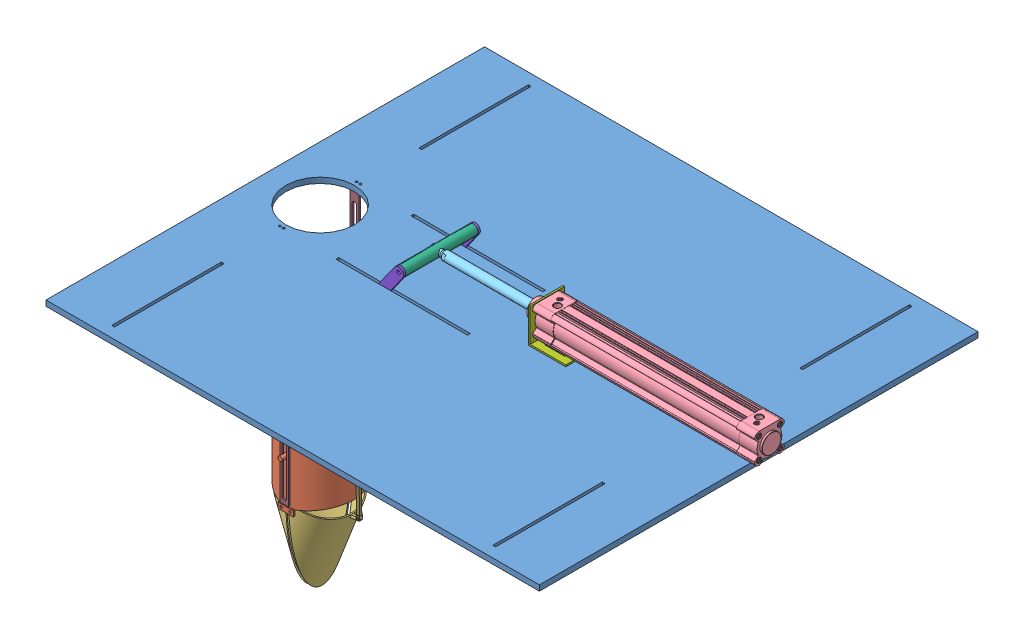
SolidWorks assembly Assem1, configuration Default. Lengths in mm.
Overall size (923.63 667.59 800).
24 component instances, 13 part files, 33 mates.
Components (placement in the parent):
- test_platform-1: test_platform [Default] at (230.5331 526.4519 836.3873) size (900 10 800)
- sub_assem_1-1: sub_assem_1 [Default] at (-22.5862 78.604 1012.0904) x (-1 0 0) z (0 0 -1) size (153.18 360.23 146)
  - sapling_cylinder-1: sapling_cylinder [Default] at (46.8806 8.4854 135.7031) size (134 210 146)
  - blade-1: blade [Default] at (44.3763 20.6048 75.7031) x (0.931286 0.364289 0) z (0 0 -1) size (71.09 159.46 120)
  - blade-2: blade [Default] at (49.414 20.6179 75.7031) x (-0.930414 0.366509 0) z (0 0 1) size (71.09 159.46 120)
- dsbc-40-300-ppva-n3-2: dsbc-40-300-ppva-n3 [Default] at (345.1649 571.4519 936.3873) x (0 0 1) z (-1 0 0) size (132 54 619.42) (flexible)
  - dsbc-40-300-ppva-n3_01-1: dsbc-40-300-ppva-n3_01 [Default] at origin size (54 54 430.3)
  - dsbc-40-300-ppva-n3_02-2: dsbc-40-300-ppva-n3_02 [Default] at (0 0 157.5173) x (0.967893 0.251361 0) z (0 0 1) size (40 40 424.9)
  - connecting_rod_1-1: connecting_rod_1 [Default] at (66 0 201.4173) x (0 1 0) z (-1 0 0) size (18 18 132)
- pneumatic_1_mount-1: pneumatic_1_mount [Default] at (376.9676 570.0281 904.8873) x (0 0 1) z (-1 0 0) size (63 63 68)
- connecting_rod-1: connecting_rod [Default] at (-60.0138 285.362 1002.3873) x (0.580128 0.814525 0) z (0 0 1) size (385.53 18 4)
- connecting_rod-2: connecting_rod [Default] at (-60.0138 285.362 866.3873) x (0.580128 0.814525 0) z (0 0 1) size (385.53 18 4)
- pneumatic_cylinder-1: pneumatic_cylinder [Default] at (30.9066 302.2621 990.5463) x (-1 0 0) z (0 -1 0) size (16 16 121.02) (flexible)
  - cylinder-1: cylinder [Default] at (30.3735 54.159 45.1726) size (16 16 94)
  - rod-1: rod [Default] at (30.3735 54.159 68.9064) x (-0.909841 -0.414956 0) z (0 0 1) size (12 12 85)
  - rod_end-1: rod_end [Default] at (30.3735 54.159 153.9064) x (0 1 0) z (0 0 -1) size (7 7 18)
- pneumatic_cylinder-3: pneumatic_cylinder [Default] at (-169.8404 302.2621 882.2284) x (1 0 0) z (0 -1 0) size (16 16 121.02) (flexible)
  - cylinder-1: cylinder [Default] at (30.3735 54.159 45.1726) size (16 16 94)
  - rod-1: rod [Default] at (30.3735 54.159 68.9064) x (0.259578 -0.965722 0) z (0 0 1) size (12 12 85)
  - rod_end-1: rod_end [Default] at (30.3735 54.159 153.9064) x (0 1 0) z (0 0 -1) size (7 7 18)
- connecting_rod_2-1: connecting_rod_2 [Default] at (-139.5802 143.7073 934.3873) x (0.019451 0.999811 0) z (0 0 1) size (71.5 5.5 7)
- connecting_rod_2-2: connecting_rod_2 [Default] at (0.5331 143.8558 934.3873) x (-0.021502 0.999769 0) z (0 0 1) size (71.5 5.5 7)
- rail-1: rail [Default] at (-77.4669 417.2853 914.2207) x (0 0 -1) z (1 0 0) size (12 430 16)
- rail-2: rail [Default] at (-61.4669 417.2853 958.554) x (0 0 1) z (-1 0 0) size (12 430 16)
Mates (geometry in assembly coordinates):
- Concentric1: concentric aligned: cylinder of test_platform-1 through (-69.4669 722.4519 936.3873) axis (0 -1 0) radius 62.5; cylinder of sub_assem_1-1/sapling_cylinder-1 through (-69.4669 292.0895 936.3873) axis (0 -1 0) radius 62
- Coincident1: coincident anti-aligned: plane of dsbc-40-300-ppva-n3-2/dsbc-40-300-ppva-n3_01-1 through (345.1649 589.6738 910.3873) normal (-1 0 0); plane of pneumatic_1_mount-1 through (345.1649 599.4519 967.8873) normal (1 0 0)
- Concentric2: concentric aligned: cylinder of dsbc-40-300-ppva-n3-2/dsbc-40-300-ppva-n3_01-1 through (345.1649 571.4519 936.3873) axis (-1 0 0) radius 17.5; cylinder of pneumatic_1_mount-1 through (410.1649 571.4519 936.3873) axis (-1 0 0) radius 20
- Concentric3: concentric aligned: cylinder of dsbc-40-300-ppva-n3-2/dsbc-40-300-ppva-n3_01-1 through (365.2843 590.4519 917.3873) axis (-1 0 0) radius 2.4585; cylinder of pneumatic_1_mount-1 through (410.1649 590.4519 917.3873) axis (-1 0 0) radius 4.75
- Coincident2: coincident aligned: plane of test_platform-1 through (395.9402 536.4519 949.1373) normal (0 0 1); plane of pneumatic_1_mount-1 through (395.9402 536.4519 949.1373) normal (0 0 1)
- Coincident3: coincident aligned: plane of test_platform-1 through (395.9402 536.4519 949.1373) normal (-1 0 0); plane of pneumatic_1_mount-1 through (395.9402 536.4519 955.1373) normal (-1 0 0)
- Coincident4: coincident anti-aligned: plane of test_platform-1 through (230.5331 536.4519 836.3873) normal (0 1 0); plane of pneumatic_1_mount-1 through (410.1649 536.4519 967.8873) normal (0 -1 0)
- Parallel1: parallel aligned: plane of test_platform-1 through (-169.4669 536.4519 1336.3873) normal (0 0 1); plane of sub_assem_1-1/sapling_cylinder-1 through (-69.4669 87.0895 999.3873) normal (0 0 1)
- Concentric4: concentric anti-aligned: cylinder of sub_assem_1-1/sapling_cylinder-1 through (-69.4669 272.0895 1009.3873) axis (0 0 1) radius 4; cylinder of connecting_rod-1 through (-69.4669 272.0895 1006.3873) axis (0 0 -1) radius 4
- Concentric5: concentric anti-aligned: cylinder of dsbc-40-300-ppva-n3-2/connecting_rod_1-1 through (143.7476 571.4519 870.3873) axis (0 0 1) radius 3; cylinder of connecting_rod-1 through (143.7476 571.4519 1006.3873) axis (0 0 -1) radius 3
- Coincident8: coincident anti-aligned: plane of dsbc-40-300-ppva-n3-2/connecting_rod_1-1 through (143.7476 571.4519 1002.3873) normal (0 0 1); plane of connecting_rod-1 through (-60.0138 285.362 1002.3873) normal (0 0 -1)
- Concentric6: concentric anti-aligned: cylinder of sub_assem_1-1/sapling_cylinder-1 through (-69.4669 272.0895 1009.3873) axis (0 0 1) radius 4; cylinder of connecting_rod-2 through (-69.4669 272.0895 870.3873) axis (0 0 -1) radius 4
- Concentric7: concentric anti-aligned: cylinder of dsbc-40-300-ppva-n3-2/connecting_rod_1-1 through (143.7476 571.4519 870.3873) axis (0 0 1) radius 3; cylinder of connecting_rod-2 through (143.7476 571.4519 870.3873) axis (0 0 -1) radius 3
- Coincident9: coincident anti-aligned: plane of dsbc-40-300-ppva-n3-2/connecting_rod_1-1 through (143.7476 571.4519 870.3873) normal (0 0 -1); plane of connecting_rod-2 through (-60.0138 285.362 870.3873) normal (0 0 1)
- Concentric8: concentric aligned: cylinder of sub_assem_1-1/sapling_cylinder-1 through (-2.4669 272.0895 936.3873) axis (-1 0 0) radius 3; cylinder of pneumatic_cylinder-1/cylinder-1 through (8.5331 272.0895 936.3873) axis (-1 0 0) radius 3
- Coincident10: coincident anti-aligned: plane of sub_assem_1-1/sapling_cylinder-1 through (-2.4669 87.0895 876.3873) normal (1 0 0); plane of pneumatic_cylinder-1/cylinder-1 through (-2.4669 278.0895 930.3873) normal (-1 0 0)
- Coincident11: coincident anti-aligned: plane of sub_assem_1-1/sapling_cylinder-1 through (-2.4669 266.0895 930.3873) normal (0 -1 0); plane of pneumatic_cylinder-1/cylinder-1 through (0.5331 266.0895 936.3873) normal (0 1 0)
- Concentric9: concentric anti-aligned: cylinder of sub_assem_1-1/sapling_cylinder-1 through (-2.4669 272.0895 936.3873) axis (-1 0 0) radius 3; cylinder of pneumatic_cylinder-3/cylinder-1 through (-147.4669 272.0895 936.3873) axis (1 0 0) radius 3
- Coincident12: coincident anti-aligned: plane of sub_assem_1-1/sapling_cylinder-1 through (-136.4669 87.0895 876.3873) normal (-1 0 0); plane of pneumatic_cylinder-3/cylinder-1 through (-136.4669 278.0895 942.3873) normal (1 0 0)
- Coincident13: coincident anti-aligned: plane of sub_assem_1-1/sapling_cylinder-1 through (-2.4669 266.0895 930.3873) normal (0 -1 0); plane of pneumatic_cylinder-3/cylinder-1 through (-139.4669 266.0895 936.3873) normal (0 1 0)
- Coincident14: coincident anti-aligned: plane of pneumatic_cylinder-3/rod_end-1 through (-142.9669 137.3558 938.3873) normal (0 0 -1); plane of connecting_rod_2-1 through (-139.5802 143.7073 938.3873) normal (0 0 1)
- Concentric11: concentric anti-aligned: cylinder of sub_assem_1-1/blade-2 through (-140.8591 77.9697 938.3873) axis (0 0 -1) radius 2; cylinder of connecting_rod_2-1 through (-140.8591 77.9697 932.8873) axis (0 0 1) radius 2
- Concentric12: concentric aligned: cylinder of pneumatic_cylinder-1/rod_end-1 through (0.5331 143.8558 939.8873) axis (0 0 -1) radius 2; cylinder of connecting_rod_2-2 through (0.5331 143.8558 938.3873) axis (0 0 -1) radius 2
- Coincident15: coincident anti-aligned: plane of pneumatic_cylinder-1/rod_end-1 through (4.0331 137.3558 938.3873) normal (0 0 -1); plane of connecting_rod_2-2 through (0.5331 143.8558 938.3873) normal (0 0 1)
- Concentric13: concentric aligned: cylinder of sub_assem_1-1/blade-1 through (1.9469 78.121 934.3873) axis (0 0 1) radius 2; cylinder of connecting_rod_2-2 through (1.9469 78.121 932.8873) axis (0 0 1) radius 2
- Coincident16: coincident anti-aligned: plane of test_platform-1 through (230.5331 526.4519 836.3873) normal (0 -1 0); plane of rail-1 through (-61.4669 526.4519 1010.8873) normal (0 1 0)
- Concentric14: concentric anti-aligned: cylinder of test_platform-1 through (-65.9669 536.4519 1006.3873) axis (0 -1 0) radius 2; cylinder of rail-1 through (-65.9669 96.4519 1006.3873) axis (0 1 0) radius 2
- Concentric15: concentric anti-aligned: cylinder of test_platform-1 through (-72.9669 536.4519 1006.3873) axis (0 -1 0) radius 2; cylinder of rail-1 through (-72.9669 96.4519 1006.3873) axis (0 1 0) radius 2
- Coincident17: coincident anti-aligned: plane of test_platform-1 through (230.5331 526.4519 836.3873) normal (0 -1 0); plane of rail-2 through (-77.4669 526.4519 861.8873) normal (0 1 0)
- Concentric16: concentric anti-aligned: cylinder of test_platform-1 through (-65.9669 536.4519 866.3873) axis (0 -1 0) radius 2; cylinder of rail-2 through (-65.9669 96.4519 866.3873) axis (0 1 0) radius 2
- Concentric17: concentric anti-aligned: cylinder of test_platform-1 through (-72.9669 536.4519 866.3873) axis (0 -1 0) radius 2; cylinder of rail-2 through (-72.9669 96.4519 866.3873) axis (0 1 0) radius 2
- Parallel3: parallel: cylinder of connecting_rod_2-1 through (-139.5802 143.7073 938.3873) axis (0 0 -1) radius 2; cylinder of connecting_rod_2-2 through (0.5331 143.8558 938.3873) axis (0 0 -1) radius 2
- Coincident18: coincident aligned: plane of pneumatic_cylinder-1/rod_end-1 through (0.5331 148.3558 936.3873) normal (0 1 0); plane of pneumatic_cylinder-3/rod_end-1 through (-139.4669 148.3558 936.3873) normal (0 1 0)
